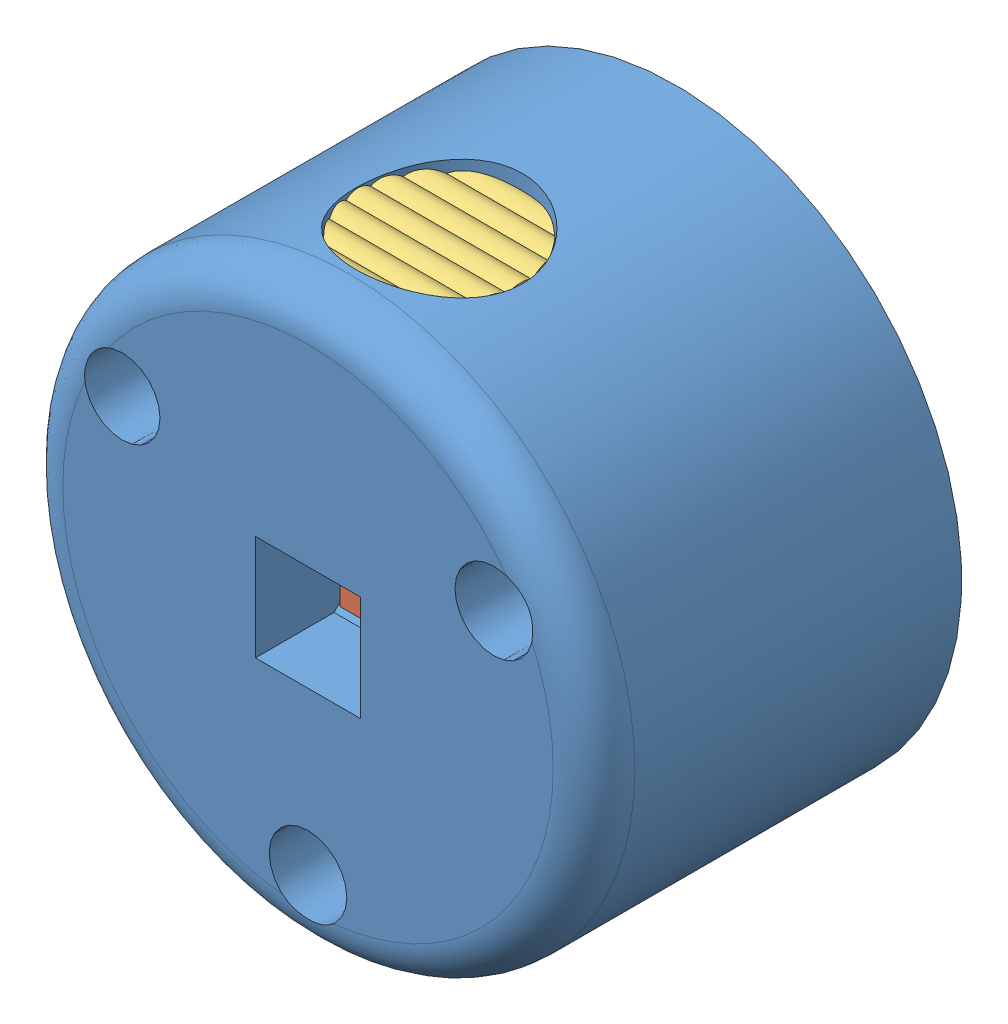
SolidWorks assembly 装配体1, configuration 默认. Lengths in mm.
Overall size (28 28 22).
3 component instances, 3 part files, 6 mates.
Components (placement in the parent):
- r1-1: r1 [默认] at (-0.1121 1.5511 17) size (28 28 22)
- mirror-1: mirror [默认] at (-2.5371 1.6261 28.5) x (0 -1 0) z (0 0 1) size (4.95 5 4.93)
- m1-1: m1 [默认] at (-0.1121 12.9675 28.575) x (0 0 1) z (-1 0 0) size (8 2 8)
Mates (geometry in assembly coordinates):
- 重合1: coincident: plane of r1-1 through (-2.6871 4.1261 26) normal (0 -1 0); plane of mirror-1 through (2.4629 4.1261 26) normal (0 1 0)
- 重合3: coincident: plane of r1-1 through (499999.8879 -1.0239 31.15) normal (0 0.707107 0.707107); plane of mirror-1 through (-2.5371 4.1261 26) normal (0 -0.707107 -0.707107)
- 重合4: coincident anti-aligned: plane of r1-1 through (2.4629 -1.0239 26) normal (-1 0 0); plane of mirror-1 through (2.4629 1.6261 28.5) normal (1 0 0)
- 重合5: coincident: plane of r1-1 through (-0.1121 12.9675 28.575) normal (0 1 0); plane of m1-1 through (-0.1121 12.9675 28.575) normal (0 -1 0)
- 同心1: concentric: cylinder of r1-1 through (-0.1121 12.9675 28.575) axis (0 1 0) radius 4.075; cylinder of m1-1 through (-0.1121 14.9675 28.575) axis (0 -1 0) radius 4
- 平行1: parallel anti-aligned: line of r1-1 through (-2.6871 4.1261 35) axis (1 0 0); line of m1-1 through (3.8426 14.7675 29.175) axis (-1 0 0)
